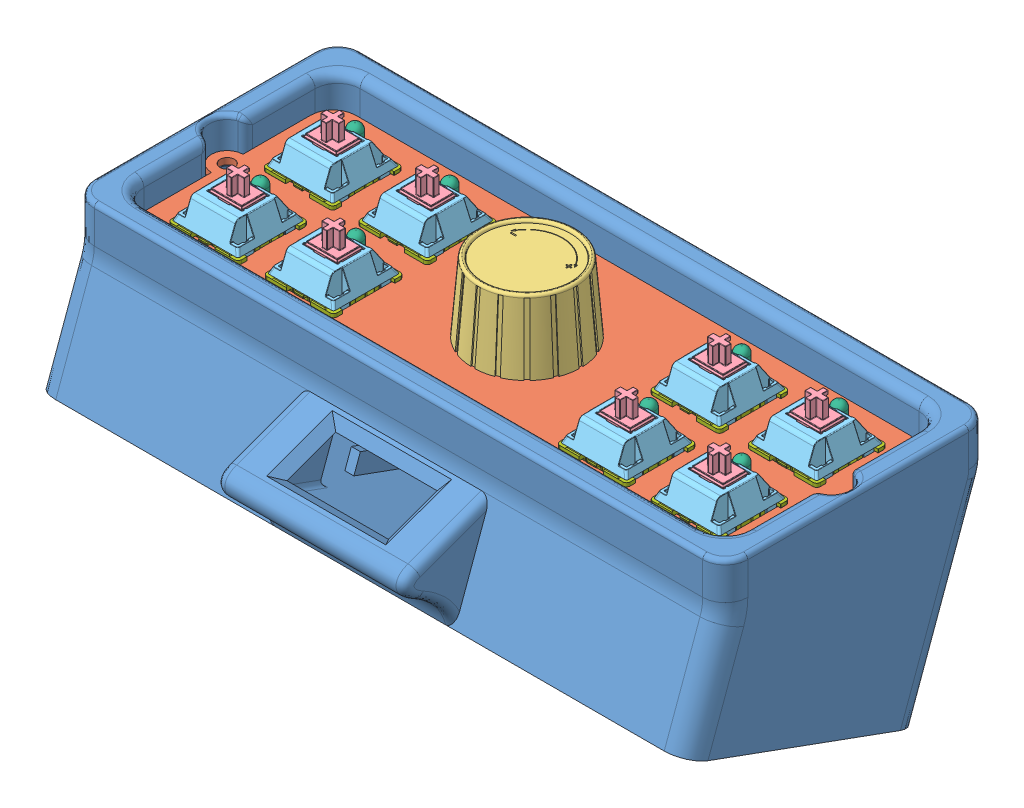
SolidWorks assembly Assemblyj, configuration Default. Lengths in mm.
Overall size (145 61.45 78.93).
52 component instances, 9 part files, 26 mates.
Components (placement in the parent):
- Body-1: Body [Default] at origin size (145 52.45 78.93)
- Plaatje-1: Plaatje [Default] at (-0.5 2.7 0.5) x (-1 0 0) z (0 0 1) size (140 4.4 47)
- Ondertoets-1: Ondertoets [Default] at (13.9476 7.9027 -50.5099)
- Volumeknop-2: Volumeknop [Default] at (-0.4973 -2.4496 0.504) size (23.98 15.6 23.98)
- MX-2: MX [Default] at (-40.25 4.4 -2.45) size (15.6 18.9 15.6)
  - MX1-1: MX1 [Default] at (7.35 2 -7.35) size (8.9 10.4 5.7)
  - MX2-1: MX2 [Default] at origin size (14.7 9.91 14.7)
  - MXled-1: MXled [Default] at (7.35 0.5 -12.292) size (3 15.3 3)
  - MX3-1: MX3 [默认] at (7.35 -0.2 -7.35) size (15.6 12.5 15.6)
  - MX4-2: MX4 [默认] at (-5.5727 -8.7 12.741) size (7.15 6.7 2.96)
- MX-3: MX [Default] at (-61.25 4.4 18.55) size (15.6 18.9 15.6)
  - MX1-1: MX1 [Default] at (7.35 2 -7.35) size (8.9 10.4 5.7)
  - MX2-1: MX2 [Default] at origin size (14.7 9.91 14.7)
  - MXled-1: MXled [Default] at (7.35 0.5 -12.292) size (3 15.3 3)
  - MX3-1: MX3 [默认] at (7.35 -0.2 -7.35) size (15.6 12.5 15.6)
  - MX4-2: MX4 [默认] at (-5.5727 -8.7 12.741) size (7.15 6.7 2.96)
- MX-4: MX [Default] at (-61.25 4.4 -2.45) size (15.6 18.9 15.6)
  - MX1-1: MX1 [Default] at (7.35 2 -7.35) size (8.9 10.4 5.7)
  - MX2-1: MX2 [Default] at origin size (14.7 9.91 14.7)
  - MXled-1: MXled [Default] at (7.35 0.5 -12.292) size (3 15.3 3)
  - MX3-1: MX3 [默认] at (7.35 -0.2 -7.35) size (15.6 12.5 15.6)
  - MX4-2: MX4 [默认] at (-5.5727 -8.7 12.741) size (7.15 6.7 2.96)
- MX-5: MX [Default] at (-40.45 4.4 18.15) size (15.6 18.9 15.6)
  - MX1-1: MX1 [Default] at (7.35 2 -7.35) size (8.9 10.4 5.7)
  - MX2-1: MX2 [Default] at origin size (14.7 9.91 14.7)
  - MXled-1: MXled [Default] at (7.35 0.5 -12.292) size (3 15.3 3)
  - MX3-1: MX3 [默认] at (7.35 -0.2 -7.35) size (15.6 12.5 15.6)
  - MX4-2: MX4 [默认] at (-5.5727 -8.7 12.741) size (7.15 6.7 2.96)
- MX-6: MX [Default] at (24.55 4.4 18.15) size (15.6 18.9 15.6)
  - MX1-1: MX1 [Default] at (7.35 2 -7.35) size (8.9 10.4 5.7)
  - MX2-1: MX2 [Default] at origin size (14.7 9.91 14.7)
  - MXled-1: MXled [Default] at (7.35 0.5 -12.292) size (3 15.3 3)
  - MX3-1: MX3 [默认] at (7.35 -0.2 -7.35) size (15.6 12.5 15.6)
  - MX4-2: MX4 [默认] at (-5.5727 -8.7 12.741) size (7.15 6.7 2.96)
- MX-7: MX [Default] at (45.55 4.4 18.55) size (15.6 18.9 15.6)
  - MX1-1: MX1 [Default] at (7.35 2 -7.35) size (8.9 10.4 5.7)
  - MX2-1: MX2 [Default] at origin size (14.7 9.91 14.7)
  - MXled-1: MXled [Default] at (7.35 0.5 -12.292) size (3 15.3 3)
  - MX3-1: MX3 [默认] at (7.35 -0.2 -7.35) size (15.6 12.5 15.6)
  - MX4-2: MX4 [默认] at (-5.5727 -8.7 12.741) size (7.15 6.7 2.96)
- MX-8: MX [Default] at (45.75 4.4 -2.85) size (15.6 18.9 15.6)
  - MX1-1: MX1 [Default] at (7.35 2 -7.35) size (8.9 10.4 5.7)
  - MX2-1: MX2 [Default] at origin size (14.7 9.91 14.7)
  - MXled-1: MXled [Default] at (7.35 0.5 -12.292) size (3 15.3 3)
  - MX3-1: MX3 [默认] at (7.35 -0.2 -7.35) size (15.6 12.5 15.6)
  - MX4-2: MX4 [默认] at (-5.5727 -8.7 12.741) size (7.15 6.7 2.96)
- MX-9: MX [Default] at (24.55 4.4 -2.45) size (15.6 18.9 15.6)
  - MX1-1: MX1 [Default] at (7.35 2 -7.35) size (8.9 10.4 5.7)
  - MX2-1: MX2 [Default] at origin size (14.7 9.91 14.7)
  - MXled-1: MXled [Default] at (7.35 0.5 -12.292) size (3 15.3 3)
  - MX3-1: MX3 [默认] at (7.35 -0.2 -7.35) size (15.6 12.5 15.6)
  - MX4-2: MX4 [默认] at (-5.5727 -8.7 12.741) size (7.15 6.7 2.96)
Mates (geometry in assembly coordinates):
- Coincident11: coincident anti-aligned: plane of Body-1 through (-67 2 0.5) normal (0 1 0); plane of Plaatje-1 through (66 2 0.5) normal (0 -1 0)
- Coincident12: coincident anti-aligned: line of Body-1 through (-67 2 -19) axis (0 0 1); line of Plaatje-1 through (-67 2 -3) axis (0 0 -1)
- Coincident13: coincident anti-aligned: line of Body-1 through (-62 2 24) axis (1 0 0); line of Plaatje-1 through (61 2 24) axis (-1 0 0)
- Coincident14: coincident anti-aligned: plane of Plaatje-1 through (66 3.4 0.5) normal (0 1 0); plane of Volumeknop-1 through (-13.25 3.4 0.5) normal (0 -1 0)
- Coincident18: coincident anti-aligned: plane of Plaatje-1 through (66 3.4 0.5) normal (0 1 0); plane of Volumeknop-1 through (-13.25 3.4 0.5) normal (0 -1 0)
- Coincident19: coincident aligned: axis of Plaatje-1 through (-0.5 -1 0.5) axis (0 1 0); line of Volumeknop-1 through (-0.5 3.4 0.5) axis (0 1 0)
- Coincident20: coincident anti-aligned: plane of Plaatje-1 through (66 3.4 0.5) normal (0 1 0); plane of Volumeknop-2 through (-10.7 3.4 0.5) normal (0 -1 0)
- Coincident21: coincident aligned: line of Plaatje-1 through (-0.5 -1 0.5) axis (0 1 0); line of Volumeknop-2 through (-0.5 3.4 0.5) axis (0 1 0)
- Coincident28: coincident anti-aligned: plane of Plaatje-1 through (66 3.4 0.5) normal (0 1 0); plane of MX-2/MX3-1 through (-32.9 3.4 -9.8) normal (0 -1 0)
- Parallel2: parallel anti-aligned: line of Plaatje-1 through (-26 3.4 -3) axis (-1 0 0); line of MX-2/MX3-1 through (-39.9 3.5 -2) axis (1 0 0)
- Coincident34: coincident aligned: line of Plaatje-1 through (-26 3.4 -3) axis (-1 0 0); line of MX-2/MX3-1 through (-35.6 3.4 -3) axis (-1 0 0)
- Coincident35: coincident anti-aligned: line of Plaatje-1 through (-40 3.4 -3) axis (0 0 -1); line of MX-2/MX3-1 through (-40 3.4 -4) axis (0 0 1)
- Coincident41: coincident aligned: line of Plaatje-1 through (-26 3.4 18) axis (-1 0 0); line of MX-3/MX3-1 through (-56.6 3.4 18) axis (-1 0 0)
- Coincident42: coincident anti-aligned: line of Plaatje-1 through (-61 3.4 18) axis (0 0 -1); line of MX-3/MX3-1 through (-61 3.4 4.85) axis (0 0 1)
- Coincident43: coincident aligned: line of Plaatje-1 through (-47 3.4 -3) axis (-1 0 0); line of MX-4/MX3-1 through (-56.6 3.4 -3) axis (-1 0 0)
- Coincident44: coincident anti-aligned: line of Plaatje-1 through (-61 3.4 -3) axis (0 0 -1); line of MX-4/MX3-1 through (-61 3.4 -16.15) axis (0 0 1)
- Coincident46: coincident: line of Plaatje-1 through (-40 3.4 4) axis (1 0 0); line of MX-5/MX3-1 through (-30.9532 3.4 4) axis (-1 0 0)
- Coincident48: coincident anti-aligned: line of Plaatje-1 through (-26 3.4 4) axis (0 0 1); line of MX-5/MX3-1 through (-26 3.4 17.15) axis (0 0 -1)
- Coincident49: coincident: line of Plaatje-1 through (25 3.4 4) axis (1 0 0); line of MX-6/MX3-1 through (37.15 3.4 4) axis (-1 0 0)
- Coincident50: coincident anti-aligned: line of Plaatje-1 through (39 3.4 4) axis (0 0 1); line of MX-6/MX3-1 through (39 3.4 17.15) axis (0 0 -1)
- Coincident51: coincident: line of Plaatje-1 through (60 3.4 18) axis (-1 0 0); line of MX-7/MX3-1 through (58.15 3.4 18) axis (-1 0 0)
- Coincident52: coincident anti-aligned: line of Plaatje-1 through (60 3.4 4) axis (0 0 1); line of MX-7/MX3-1 through (60 3.4 17.55) axis (0 0 -1)
- Coincident53: coincident: line of Plaatje-1 through (46 3.4 -17) axis (1 0 0); line of MX-8/MX3-1 through (50.4 3.4 -17) axis (-1 0 0)
- Coincident54: coincident anti-aligned: line of Plaatje-1 through (46 3.4 -3) axis (0 0 -1); line of MX-8/MX3-1 through (46 3.4 -16.55) axis (0 0 1)
- Coincident55: coincident: line of Plaatje-1 through (39 3.4 -17) axis (0 0 1); line of MX-9/MX3-1 through (39 3.4 -3.45) axis (0 0 -1)
- Coincident56: coincident aligned: line of Plaatje-1 through (39 3.4 -3) axis (-1 0 0); line of MX-9/MX3-1 through (29.2 3.4 -3) axis (-1 0 0)
